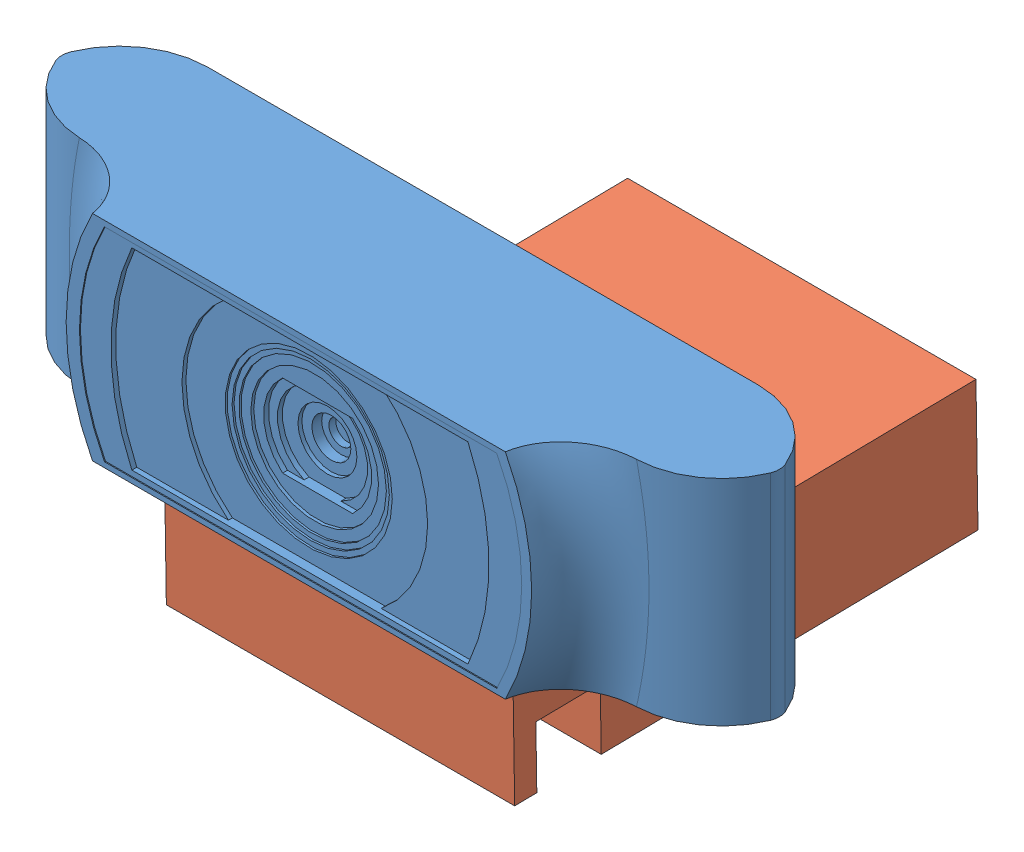
SolidWorks assembly CameraMount, configuration Default. Lengths in mm.
Overall size (92.68 44.39 65.89).
2 component instances, 2 part files, 2 mates.
Components (placement in the parent):
- LogitechC920_camera-1: LogitechC920_camera [Default] at (-48.8625 43.709 78.1959) size (92.68 27.69 37.04)
- Part1^CameraMount-1: Part1^CameraMount [Default] at (2.5933 43.6448 94.029) x (1 0 0) z (0 -0.015593 0.999878) size (49 21 59.86) (virtual)
Mates (geometry in assembly coordinates):
- Concentric1: concentric aligned: cylinder of LogitechC920_camera-1 through (23.9085 46.0203 95.4962) axis (-1 0 0) radius 1.25; cylinder of Part1^CameraMount-1 through (22.6225 46.0203 95.4962) axis (-1 0 0) radius 1.25
- Distance1: distance = 1 mm anti-aligned: plane of Part1^CameraMount-1 through (20.6225 47.9978 96.9572) normal (1 0 0); plane of LogitechC920_camera-1 through (21.6225 43.709 78.4499) normal (-1 0 0)
